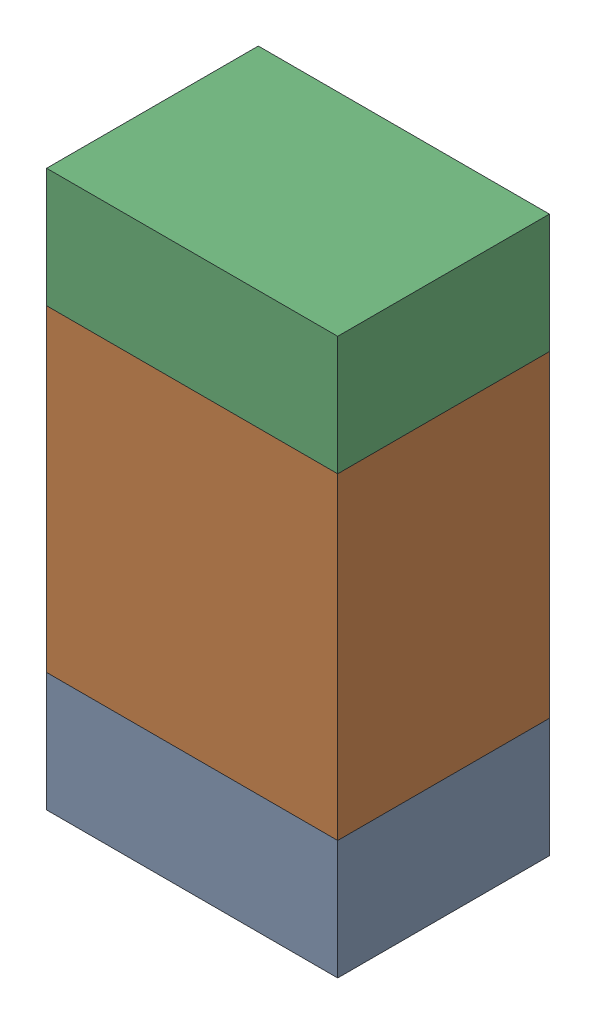
SolidWorks assembly R700PCB, configuration Default. Lengths in mm.
Overall size (0.55 1.05 0.4).
6 component instances, 2 part files, 0 mates.
Components (placement in the parent):
- 846483288-1: 846483288 [Default] at (115.9001 121.3876 -2.0638) size (0.55 0.22 0.4)
  - Extruded_12-1: Extruded_12 [Default] at origin size (0.55 0.22 0.4)
- 846483424-1: 846483424 [Default] at (115.9001 121.8001 -2.0638) size (0.55 0.6 0.4)
  - Extruded_13-1: Extruded_13 [Default] at origin size (0.55 0.6 0.4)
- 846483288-2: 846483288 [Default] at (115.9001 122.2126 -2.0638) size (0.55 0.22 0.4)
  - Extruded_12-1: Extruded_12 [Default] at origin size (0.55 0.22 0.4)
